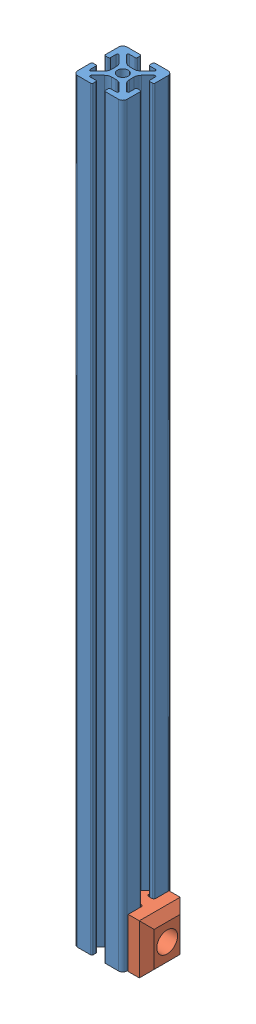
SolidWorks assembly Test, configuration Default. Lengths in mm.
Overall size (27.9 304.8 20).
2 component instances, 2 part files, 5 mates.
Components (placement in the parent):
- 5537T501_T-Slotted Framing-1: 5537T501_T-Slotted Framing [5537T501] at (-10.8858 152.4 -0.7336) x (1 0 0) z (0 1 0) size (20 20 304.8)
- Part7-1: Part7 [Default] x (1 0 0) z (0 1 0) size (13.9 16.5 20)
Mates (geometry in assembly coordinates):
- Coincident1: coincident anti-aligned: plane of 5537T501_T-Slotted Framing-1 through (-7.8858 0 8.7664) normal (0 -1 0)
- InPlace1: in place: plane of Part7-1 through (0 0 0) normal (0 1 0); moOrthogonalPlaneRef_w of Part7-1 through (0 0 0) normal (0 0 -1); plane of Part7-1 through (0 0 0) normal (1 0 0); unknown of Part7-1
- Coincident5: coincident aligned: 
- Coincident6: coincident aligned: plane of Part7-1 through (0 0 0) normal (0 0 -1)
- Coincident7: coincident anti-aligned: plane of Part7-1 through (0 0 0) normal (1 0 0)
